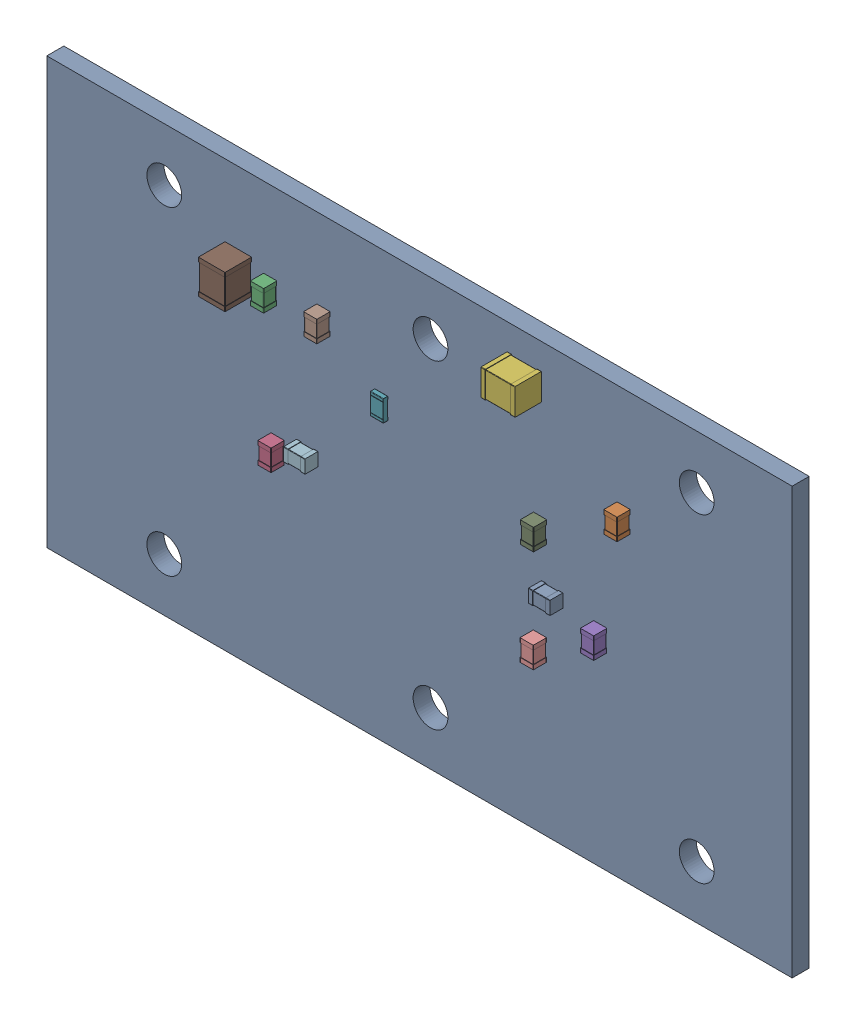
SolidWorks assembly S-Band Amplifier, configuration Default. Lengths in mm.
Overall size (70 40 4.15).
26 component instances, 4 part files, 0 mates.
Components (placement in the parent):
- S-Band Amplifier(2)-1: S-Band Amplifier(2) [Default] at origin size (70 40 4.15)
  - C_0805_2012Metric-1: C_0805_2012Metric [Default] at (91.5 -90 1.65) size (2 1.25 1.25)
    - C_0805_2012Metric-0-1: C_0805_2012Metric-0 [Default] at origin size (2 1.25 1.25)
  - C_0805_2012Metric-2: C_0805_2012Metric [Default] at (98.19 -80.45 1.65) x (0 -1 0) z (0 0 1) size (2 1.25 1.25)
    - C_0805_2012Metric-0-1: C_0805_2012Metric-0 [Default] at origin size (2 1.25 1.25)
  - C_0805_2012Metric-3: C_0805_2012Metric [Default] at (65 -78.45 1.65) x (0 1 0) z (0 0 1) size (2 1.25 1.25)
    - C_0805_2012Metric-0-1: C_0805_2012Metric-0 [Default] at origin size (2 1.25 1.25)
  - C_0805_2012Metric-4: C_0805_2012Metric [Default] at (65.7 -91.075 1.65) x (0 -1 0) z (0 0 1) size (2 1.25 1.25)
    - C_0805_2012Metric-0-1: C_0805_2012Metric-0 [Default] at origin size (2 1.25 1.25)
  - C_0805_2012Metric-5: C_0805_2012Metric [Default] at (96 -91.2 1.65) x (0 1 0) z (0 0 1) size (2 1.25 1.25)
    - C_0805_2012Metric-0-1: C_0805_2012Metric-0 [Default] at origin size (2 1.25 1.25)
  - C_1210_3225Metric-1: C_1210_3225Metric [Default] at (88.875 -73.63 1.65) x (-1 0 0) z (0 0 1) size (3.2 2.5 2.5)
    - C_1210_3225Metric-1-1: C_1210_3225Metric-1 [Default] at origin size (3.2 2.5 2.5)
  - R_0805_2012Metric-1: R_0805_2012Metric [Default] at (75.45 -82.6 1.65) x (0 -1 0) z (0 0 1) size (2 1.2 0.45)
    - R_0805_2012Metric-2-1: R_0805_2012Metric-2 [Default] at origin size (2 1.2 0.45)
  - C_0805_2012Metric-6: C_0805_2012Metric [Default] at (70 -78.45 1.65) x (0 1 0) z (0 0 1) size (2 1.25 1.25)
    - C_0805_2012Metric-0-1: C_0805_2012Metric-0 [Default] at origin size (2 1.25 1.25)
  - C_0805_2012Metric-7: C_0805_2012Metric [Default] at (90.35 -85.2 1.65) x (0 1 0) z (0 0 1) size (2 1.25 1.25)
    - C_0805_2012Metric-0-1: C_0805_2012Metric-0 [Default] at origin size (2 1.25 1.25)
  - C_0805_2012Metric-8: C_0805_2012Metric [Default] at (90.325 -94.8 1.65) x (0 -1 0) z (0 0 1) size (2 1.25 1.25)
    - C_0805_2012Metric-0-1: C_0805_2012Metric-0 [Default] at origin size (2 1.25 1.25)
  - C_1210_3225Metric-2: C_1210_3225Metric [Default] at (62 -78.3 1.65) x (0 1 0) z (0 0 1) size (3.2 2.5 2.5)
    - C_1210_3225Metric-1-1: C_1210_3225Metric-1 [Default] at origin size (3.2 2.5 2.5)
  - C_0805_2012Metric-9: C_0805_2012Metric [Default] at (68.5 -90 1.65) size (2 1.25 1.25)
    - C_0805_2012Metric-0-1: C_0805_2012Metric-0 [Default] at origin size (2 1.25 1.25)
  - S-Band Amplifier_PCB-1: S-Band Amplifier_PCB [Default] at origin size (70 40 1.6)
